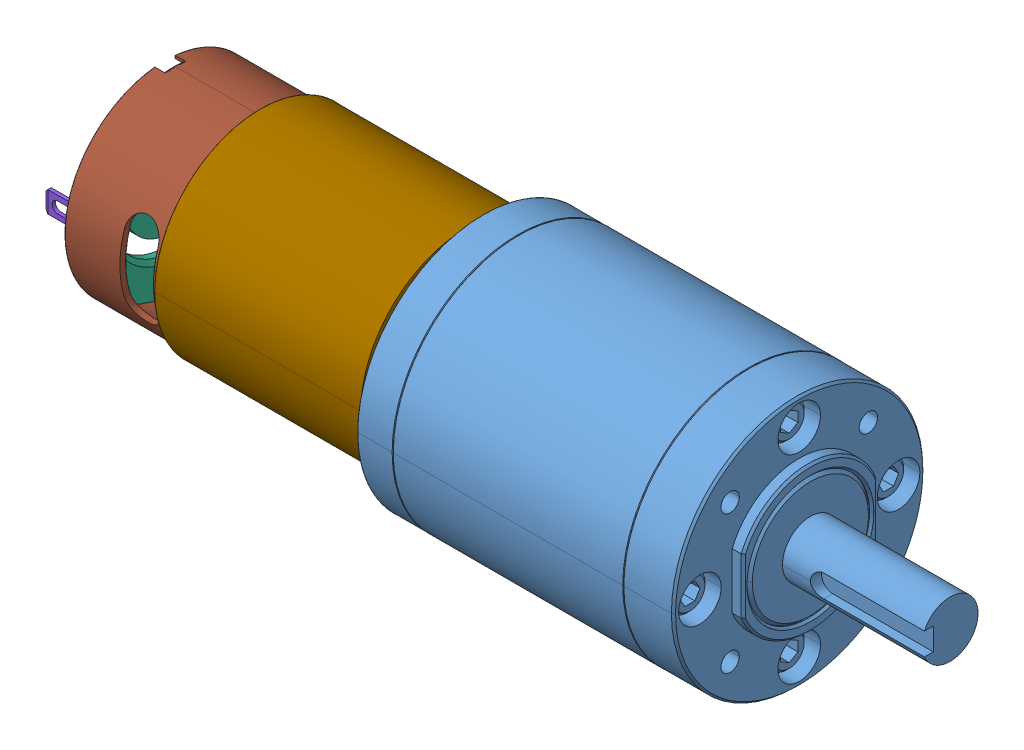
SolidWorks assembly PG71+w+9015, configuration Default. Lengths in mm.
Overall size (147.53 45 45).
14 component instances, 11 part files, 0 mates.
Components (placement in the parent):
- PG-71 Gearbox-1: PG-71 Gearbox [Default] at (-71.222 22.4567 22.3261) size (83.52 45 45)
- AM-0912-1: AM-0912 [Default] at (-29.4068 20.8663 23.4492) x (-1 0 0) z (0 -1 0) size (82.02 37.83 37.47)
  - AM-0912 cap bushing-1: AM-0912 cap bushing [Default] at (31.302 1.123 -1.5904) size (3.04 8.08 8.08)
  - AM-0912 red dot-1: AM-0912 red dot [Default] at (32.318 13.4019 -9.2612) size (0.13 2.92 2.92)
  - AM-0912 terminal housing-1: AM-0912 terminal housing [Default] at (30.286 -13.101 -1.5904) x (-1 0 0) z (0 0 1) size (4.06 4.83 19.05)
  - AM-0912 armature-1: AM-0912 armature [Default] at (1.734 1.123 -1.5904) size (2.54 33.69 33.69)
  - AM-0912 end cap-1: AM-0912 end cap [Default] at (24.952 1.123 -1.5904) size (6.48 34.65 34.41)
  - AM-0912 shaft-1: AM-0912 shaft [Default] at (-32.682 1.123 -1.5904) x (1 0 0) z (0 0.95755 0.288268) size (80.92 3.2 3.2)
  - AM-0912 terminal-1: AM-0912 terminal [Default] at (29.27 -13.055 -1.5854) size (10.06 0.6 3.8)
  - AM-0912 shield-1: AM-0912 shield [Default] at (-21.634 1.123 -1.5904) x (1 0 0) z (0 -1 0) size (36.88 37.47 37.83)
  - AM-0912 terminal housing-2: AM-0912 terminal housing [Default] at (30.286 15.347 -1.5904) x (-1 0 0) z (0 0 -1) size (4.06 4.83 19.05)
  - AM-0912 output bushing-1: AM-0912 output bushing [Default] at (-28.166 1.123 -1.5904) size (4.5 10.97 10.97)
  - AM-0912 housing-1: AM-0912 housing [Default] at (32.318 1.123 -1.5904) size (61.5 35.8 35.8)
  - AM-0912 terminal-2: AM-0912 terminal [Default] at (29.27 15.301 -1.5954) size (10.06 0.6 3.8)
